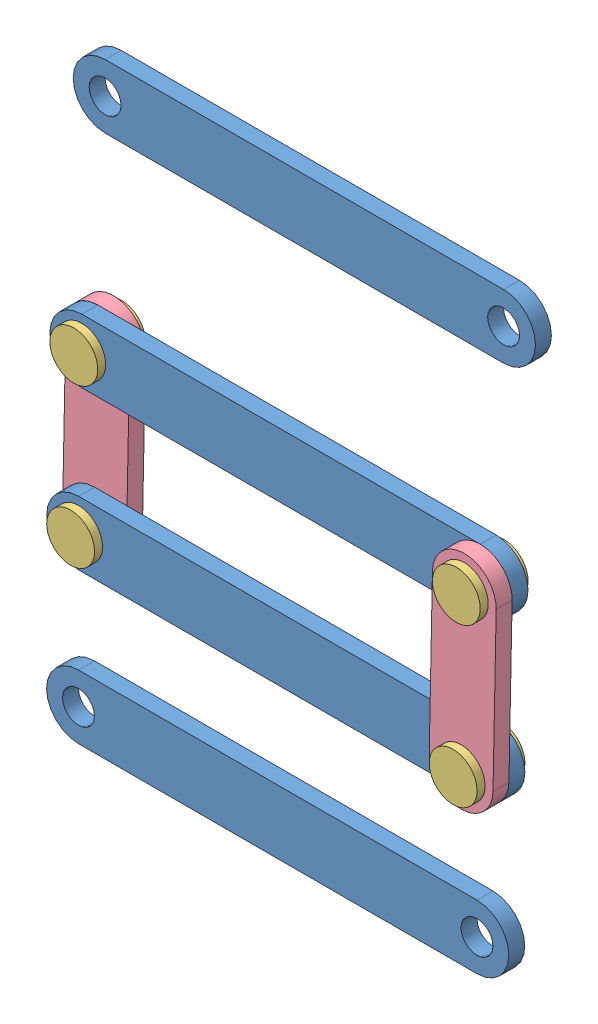
SolidWorks assembly Mechanism_1, configuration Default. Lengths in mm.
Overall size (96.25 110.93 36.91).
18 component instances, 4 part files, 27 mates.
Components (placement in the parent):
- Link1-1: Link1 [Default] at origin size (58 8 2)
- Pin_body-2: Pin_body [Default] at origin size (4 4 4)
- Pin_head-4: Pin_head [Default] at (0 0 -1) size (6 6 1)
- Pin_head-5: Pin_head [Default] at (0 0 4) size (6 6 1)
- Small_link-1: Small_link [Default] at (0.3981 19.996 2) x (-0.019906 -0.999802 0) z (0 0 1) size (28 8 2)
- Link1-2: Link1 [Default] at (0.3981 19.996 0) size (58 8 2)
- Pin_body-3: Pin_body [Default] at (0.3981 19.996 0) size (4 4 4)
- Pin_head-6: Pin_head [Default] at (0.3981 19.996 -1) x (0.994005 0.109338 0) z (0 0 1) size (6 6 1)
- Pin_head-7: Pin_head [Default] at (0.3981 19.996 4) size (6 6 1)
- Small_link-2: Small_link [Default] at (-50 0 -2) x (0.019906 0.999802 0) z (0 0 1) size (28 8 2)
- Pin_body-4: Pin_body [Default] at (-49.6019 19.996 -2) size (4 4 4)
- Pin_head-8: Pin_head [Default] at (-49.6019 19.996 -3) size (6 6 1)
- Pin_head-9: Pin_head [Default] at (-49.6019 19.996 2) size (6 6 1)
- Pin_body-5: Pin_body [Default] at (-50 0 -2) size (4 4 4)
- Pin_head-10: Pin_head [Default] at (-50 0 -3) size (6 6 1)
- Pin_head-11: Pin_head [Default] at (-50 0 2) size (6 6 1)
- Link1-3: Link1 [Default] at (30.3841 76.1887 27.0577) size (58 8 2)
- Link1-4: Link1 [Default] at (-7.8645 -26.7391 -7.8505) size (58 8 2)
Mates (geometry in assembly coordinates):
- Concentric4: concentric: cylinder of Link1-1 through (0 0 2) axis (0 0 -1) radius 2; cylinder of Pin_body-2 through (0 0 4) axis (0 0 -1) radius 2
- Coincident20: coincident: circle of Link1-1; plane of Pin_body-2 through (0 0 0) normal (0 0 -1)
- Coincident21: coincident: circle of Link1-1; circle of Pin_head-4
- Coincident22: coincident: circle of Pin_body-2; circle of Pin_head-5
- Concentric6: concentric: cylinder of Pin_body-2 through (0 0 4) axis (0 0 -1) radius 2; cylinder of Small_link-1 through (0 0 4) axis (0 0 -1) radius 2
- Coincident24: coincident: plane of Link1-1 through (0 0 2) normal (0 0 1); plane of Small_link-1 through (0.3981 19.996 2) normal (0 0 -1)
- Concentric7: concentric: cylinder of Small_link-1 through (0.3981 19.996 4) axis (0 0 -1) radius 2; cylinder of Link1-2 through (0.3981 19.996 2) axis (0 0 -1) radius 2
- Coincident25: coincident: plane of Small_link-1 through (0.3981 19.996 2) normal (0 0 -1); plane of Link1-2 through (0.3981 19.996 2) normal (0 0 1)
- Concentric8: concentric: cylinder of Link1-2 through (0.3981 19.996 2) axis (0 0 -1) radius 2; cylinder of Pin_body-3 through (0.3981 19.996 4) axis (0 0 -1) radius 2
- Coincident27: coincident: plane of Link1-2 through (0.3981 19.996 0) normal (0 0 -1); plane of Pin_body-3 through (0.3981 19.996 0) normal (0 0 -1)
- Coincident28: coincident: circle of Pin_body-3; circle of Pin_head-6
- Coincident29: coincident: circle of Small_link-1; circle of Pin_head-7
- Concentric9: concentric: cylinder of Link1-2 through (-49.6019 19.996 2) axis (0 0 -1) radius 2; cylinder of Small_link-2 through (-49.6019 19.996 0) axis (0 0 -1) radius 2
- Coincident30: coincident: plane of Link1-2 through (0.3981 19.996 0) normal (0 0 -1); plane of Small_link-2 through (-50 0 0) normal (0 0 1)
- Concentric10: concentric: cylinder of Link1-1 through (-50 0 2) axis (0 0 -1) radius 2; cylinder of Small_link-2 through (-50 0 0) axis (0 0 -1) radius 2
- Coincident31: coincident: plane of Link1-1 through (0 0 0) normal (0 0 -1); plane of Small_link-2 through (-50 0 0) normal (0 0 1)
- Concentric11: concentric: cylinder of Link1-2 through (-49.6019 19.996 2) axis (0 0 -1) radius 2; cylinder of Pin_body-4 through (-49.6019 19.996 2) axis (0 0 -1) radius 2
- Coincident33: coincident: plane of Link1-2 through (0.3981 19.996 2) normal (0 0 1); plane of Pin_body-4 through (-49.6019 19.996 2) normal (0 0 1)
- Coincident34: coincident: circle of Pin_body-4; circle of Pin_head-8
- Coincident35: coincident: circle of Pin_body-4; circle of Pin_head-9
- Concentric12: concentric: cylinder of Small_link-2 through (-50 0 0) axis (0 0 -1) radius 2; cylinder of Pin_body-5 through (-50 0 2) axis (0 0 -1) radius 2
- Coincident36: coincident: plane of Small_link-2 through (-50 0 -2) normal (0 0 -1); plane of Pin_body-5 through (-50 0 -2) normal (0 0 -1)
- Coincident38: coincident: circle of Pin_body-5; circle of Pin_head-10
- Coincident39: coincident: circle of Pin_body-5; circle of Pin_head-11
- Coincident40: coincident: plane of Link1-2 through (0.3981 19.996 0) normal (0 0 -1); plane of Small_link-2 through (-50 0 0) normal (0 0 1)
- Coincident41: coincident: plane of Link1-2 through (0.3981 19.996 0) normal (0 0 -1); plane of Small_link-2 through (-50 0 0) normal (0 0 1)
- Coincident42: coincident: plane of Link1-1 through (0 0 0) normal (0 0 -1); plane of Small_link-2 through (-50 0 0) normal (0 0 1)
